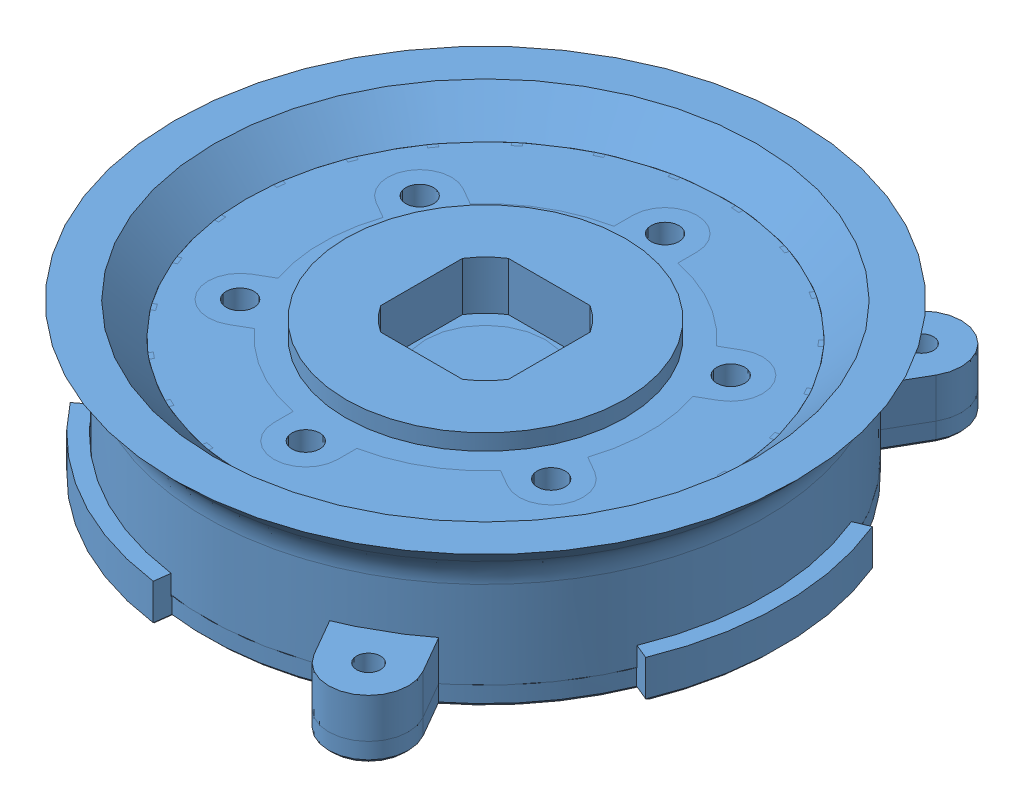
SolidWorks assembly Wheel Mold Setup, configuration Default. Lengths in mm.
Overall size (106.68 24.77 100.69).
4 component instances, 1 part files, 12 mates.
Components (placement in the parent):
- Casted Wheel-1: Casted Wheel [Mold Bottom] x (-1 0 0) z (0 0 1) size (104.27 14.61 100.69)
- Casted Wheel-2: Casted Wheel [Mold Top] x (-1 0 0) z (0 0 1) size (106.68 21.59 100.69)
- Casted Wheel-3: Casted Wheel [Hub] x (-1 0 0) z (0 0 1) size (59.65 19.05 67.31)
- Casted Wheel-4: Casted Wheel [Tire] x (-1 0 0) z (0 0 1) size (76.19 16.51 76.2)
Mates (geometry in assembly coordinates):
- Coincident1: coincident anti-aligned: plane of Casted Wheel-1 through (0 0 0) normal (0 -1 0)
- Coincident2: coincident aligned: plane of Casted Wheel-1 through (0 0 0) normal (0 0 1)
- Coincident3: coincident anti-aligned: plane of Casted Wheel-1 through (0 0 0) normal (-1 0 0)
- Coincident4: coincident aligned: plane of Casted Wheel-1 through (0 0 0) normal (0 0 1); plane of Casted Wheel-2 through (0 0 0) normal (0 0 1)
- Coincident5: coincident aligned: plane of Casted Wheel-1 through (0 0 0) normal (0 -1 0); plane of Casted Wheel-2 through (0 0 0) normal (0 -1 0)
- Coincident6: coincident aligned: plane of Casted Wheel-1 through (0 0 0) normal (-1 0 0); plane of Casted Wheel-2 through (0 0 0) normal (-1 0 0)
- Coincident7: coincident aligned: plane of Casted Wheel-1 through (0 0 0) normal (0 0 1); plane of Casted Wheel-3 through (0 0 0) normal (0 0 1)
- Coincident8: coincident aligned: plane of Casted Wheel-1 through (0 0 0) normal (0 -1 0); plane of Casted Wheel-3 through (0 0 0) normal (0 -1 0)
- Coincident9: coincident aligned: plane of Casted Wheel-1 through (0 0 0) normal (-1 0 0); plane of Casted Wheel-3 through (0 0 0) normal (-1 0 0)
- Coincident10: coincident aligned: plane of Casted Wheel-1 through (0 0 0) normal (0 0 1); plane of Casted Wheel-4 through (0 0 0) normal (0 0 1)
- Coincident11: coincident aligned: plane of Casted Wheel-1 through (0 0 0) normal (0 -1 0); plane of Casted Wheel-4 through (0 0 0) normal (0 -1 0)
- Coincident12: coincident aligned: plane of Casted Wheel-1 through (0 0 0) normal (-1 0 0); plane of Casted Wheel-4 through (0 0 0) normal (-1 0 0)
